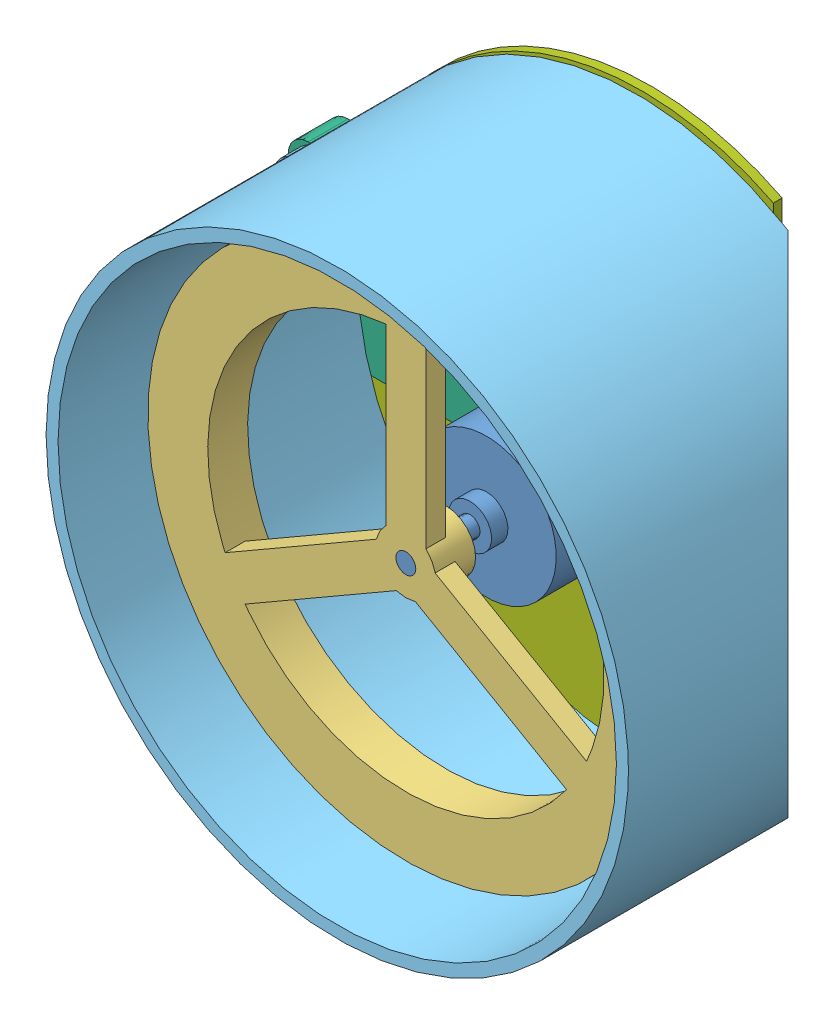
SolidWorks assembly Axis, configuration Default. Lengths in mm.
Overall size (176.68 176.68 95.5).
17 component instances, 7 part files, 42 mates.
Components (placement in the parent):
- Motor-1: Motor [Default] x (0.707107 0.707107 0) z (0.707107 -0.707107 0) size (35 53.5 35)
- Motor Plate-1: Motor Plate [Default] at (0 0 -26.65) x (0.707107 0.707107 0) z (-0.707107 0.707107 0) size (50 2.8 50)
- Reaction Wheel-1: Reaction Wheel [Default] at (0 0 26.75) x (0.5 -0.866025 0) z (-0.866025 -0.5 0) size (129.34 10 129.34)
- Screw-1: Screw [M3x5.5 Flat] at (8.4853 8.4853 -23.3783) x (0.707107 0.707107 0) z (-0.707107 0.707107 0) size (5 7.2 5)
- Screw-2: Screw [M3x5.5 Flat] at (6.5407 -6.5407 -23.3783) x (0.707107 0.707107 0) z (-0.707107 0.707107 0) size (5 7.2 5)
- Screw-3: Screw [M3x5.5 Flat] at (-6.5407 6.5407 -23.3783) x (0.707107 0.707107 0) z (-0.707107 0.707107 0) size (5 7.2 5)
- Screw-4: Screw [M3x5.5 Flat] at (-8.4853 -8.4853 -23.3783) x (0.707107 0.707107 0) z (-0.707107 0.707107 0) size (5 7.2 5)
- Screw-5: Screw [M3x25 Flat] at (-14.92 14.92 -38.525) x (0.999986 0.005309 0) z (0.005309 -0.999986 0) size (6 25 6)
- Screw-6: Screw [M3x25 Flat] at (-14.92 -14.92 -38.525) x (0.707107 0.707107 0) z (0.707107 -0.707107 0) size (6 25 6)
- Screw-7: Screw [M3x25 Flat] at (14.92 -14.92 -38.525) x (0.707107 0.707107 0) z (0.707107 -0.707107 0) size (6 25 6)
- Screw-8: Screw [M3x25 Flat] at (14.92 14.92 -38.525) x (0.707107 0.707107 0) z (0.707107 -0.707107 0) size (6 25 6)
- Shield-1: Shield [Default] at (0 0 6.45) size (159 146 75)
- Screw-9: Screw [M3x25 Flat] at (-79.5 14.92 -39.875) x (0.707107 0.707107 0) z (0.707107 -0.707107 0) size (6 25 6)
- Screw-10: Screw [M3x25 Flat] at (-79.5 -14.92 -39.875) x (0.707107 0.707107 0) z (0.707107 -0.707107 0) size (6 25 6)
- Shock Plate-1: Shock Plate [Default] at (-32.29 0 -36.05) x (-1 0 0) z (0 1 0) size (110 10 42.84)
- Rear Shield-1: Rear Shield [Wire Holes] at (0.0004 0 -33.5) x (1 0 0) z (0 -1 0) size (105.21 2.2 71.58)
- Rear Shield-2: Rear Shield [Default] at (0.0004 0 -33.5) x (1 0 0) z (0 1 0) size (105.21 2.2 71.58)
Mates (geometry in assembly coordinates):
- Coincident2: coincident aligned: plane of Motor-1 through (0 0 0) normal (0 0 1)
- Concentric1: concentric anti-aligned: cylinder of Motor-1 through (0 0 -45.7891) axis (0 0 -1) radius 2.5; cylinder of Motor Plate-1 through (0 0 -28.05) axis (0 0 1) radius 5.75
- Coincident4: coincident anti-aligned: plane of Motor-1 through (1.7678 1.7678 -25.25) normal (0 0 -1); plane of Motor Plate-1 through (14.92 -14.92 -25.25) normal (0 0 1)
- Concentric2: concentric anti-aligned: cylinder of Motor-1 through (8.4853 8.4853 -20.25) axis (0 0 -1) radius 1.5; cylinder of Motor Plate-1 through (8.4853 8.4853 -28.05) axis (0 0 1) radius 1.5
- Concentric3: concentric anti-aligned: cylinder of Motor-1 through (6.5407 -6.5407 -20.25) axis (0 0 -1) radius 1.5; cylinder of Motor Plate-1 through (6.5407 -6.5407 -28.05) axis (0 0 1) radius 1.5
- Concentric4: concentric aligned: cylinder of Motor Plate-1 through (8.4853 8.4853 -28.05) axis (0 0 1) radius 1.5; cylinder of Screw-1 through (8.4853 8.4853 -17.6716) axis (0 0 1) radius 1.35
- Coincident6: coincident aligned: cone of Motor Plate-1 through (8.4853 8.4853 -26.35) axis (0 0 1); cone of Screw-1 through (8.4853 8.4853 -26.1283) axis (0 0 1)
- Concentric9: concentric aligned: cylinder of Motor Plate-1 through (6.5407 -6.5407 -28.05) axis (0 0 1) radius 1.5; cylinder of Screw-2 through (6.5407 -6.5407 -17.6716) axis (0 0 1) radius 1.35
- Coincident7: coincident aligned: cone of Motor Plate-1 through (6.5407 -6.5407 -26.35) axis (0 0 1); cone of Screw-2 through (6.5407 -6.5407 -26.1283) axis (0 0 1)
- Concentric10: concentric aligned: cylinder of Motor Plate-1 through (-6.5407 6.5407 -28.05) axis (0 0 1) radius 1.5; cylinder of Screw-3 through (-6.5407 6.5407 -17.6716) axis (0 0 1) radius 1.35
- Coincident8: coincident aligned: cone of Motor Plate-1 through (-6.5407 6.5407 -26.35) axis (0 0 1); cone of Screw-3 through (-6.5407 6.5407 -26.1283) axis (0 0 1)
- Concentric11: concentric aligned: cylinder of Motor Plate-1 through (-8.4853 -8.4853 -28.05) axis (0 0 1) radius 1.5; cylinder of Screw-4 through (-8.4853 -8.4853 -17.6716) axis (0 0 1) radius 1.35
- Coincident9: coincident aligned: cone of Motor Plate-1 through (-8.4853 -8.4853 -26.35) axis (0 0 1); cone of Screw-4 through (-8.4853 -8.4853 -26.1283) axis (0 0 1)
- Concentric12: concentric anti-aligned: cylinder of Motor-1 through (0 0 -45.7891) axis (0 0 -1) radius 2.5; cylinder of Reaction Wheel-1 through (0 0 16.75) axis (0 0 1) radius 2.5
- Coincident10: coincident aligned: plane of Motor-1 through (0 0 26.75) normal (0 0 1); plane of Reaction Wheel-1 through (0 0 26.75) normal (0 0 1)
- Parallel1: parallel aligned: plane of Reaction Wheel-1 through (5 5.5902 21.75) normal (1 0 0)
- Concentric13: concentric anti-aligned: cylinder of Motor Plate-1 through (14.92 14.92 -28.05) axis (0 0 1) radius 1.5; cylinder of Screw-8 through (14.92 14.92 -44.2316) axis (0 0 -1) radius 1.35
- Coincident12: coincident aligned: cone of Motor Plate-1 through (14.92 14.92 -25.25) axis (0 0 -1); cone of Screw-8 through (14.92 14.92 -26.85) axis (0 0 -1)
- Concentric14: concentric anti-aligned: cylinder of Motor Plate-1 through (-14.92 14.92 -28.05) axis (0 0 1) radius 1.5; cylinder of Screw-5 through (-14.92 14.92 -44.2316) axis (0 0 -1) radius 1.35
- Coincident13: coincident aligned: cone of Motor Plate-1 through (-14.92 14.92 -25.25) axis (0 0 -1); cone of Screw-5 through (-14.92 14.92 -26.85) axis (0 0 -1)
- Concentric15: concentric anti-aligned: cylinder of Motor Plate-1 through (14.92 -14.92 -28.05) axis (0 0 1) radius 1.5; cylinder of Screw-7 through (14.92 -14.92 -44.2316) axis (0 0 -1) radius 1.35
- Coincident14: coincident aligned: cone of Motor Plate-1 through (14.92 -14.92 -25.25) axis (0 0 -1); cone of Screw-7 through (14.92 -14.92 -26.85) axis (0 0 -1)
- Concentric16: concentric anti-aligned: cylinder of Motor Plate-1 through (-14.92 -14.92 -28.05) axis (0 0 1) radius 1.5; cylinder of Screw-6 through (-14.92 -14.92 -44.2316) axis (0 0 -1) radius 1.35
- Coincident15: coincident aligned: cone of Motor Plate-1 through (-14.92 -14.92 -25.25) axis (0 0 -1); cone of Screw-6 through (-14.92 -14.92 -26.85) axis (0 0 -1)
- Concentric18: concentric anti-aligned: cylinder of Reaction Wheel-1 through (0 0 16.75) axis (0 0 1) radius 64.67; cylinder of Shield-1 through (0 0 43.95) axis (0 0 -1) radius 70
- Concentric19: concentric aligned: cylinder of Screw-5 through (-14.92 14.92 -44.2316) axis (0 0 -1) radius 1.35; cylinder of Shield-1 through (-14.92 14.92 -28.05) axis (0 0 -1) radius 1.5
- Coincident16: coincident anti-aligned: plane of Motor Plate-1 through (14.92 -14.92 -28.05) normal (0 0 -1); plane of Shield-1 through (73.002 27.92 -28.05) normal (0 0 1)
- Coincident18: coincident aligned: plane of Shield-1 through (0 0 6.45) normal (0 1 0)
- Coincident20: coincident aligned: plane of Shield-1 through (0 0 6.45) normal (1 0 0)
- Concentric20: concentric aligned: cylinder of Shield-1 through (-79.5 14.92 -26.05) axis (0 0 -1) radius 1.5; cylinder of Screw-9 through (-79.5 14.92 -45.5816) axis (0 0 -1) radius 1.35
- Concentric21: concentric aligned: cylinder of Shield-1 through (-79.5 -14.92 -26.05) axis (0 0 -1) radius 1.5; cylinder of Screw-10 through (-79.5 -14.92 -45.5816) axis (0 0 -1) radius 1.35
- Coincident21: coincident aligned: cone of Shield-1 through (-79.5 14.92 -26.05) axis (0 0 -1); cone of Screw-9 through (-79.5 14.92 -28.2) axis (0 0 -1)
- Coincident22: coincident aligned: cone of Shield-1 through (-79.5 -14.92 -26.05) axis (0 0 -1); cone of Screw-10 through (-79.5 -14.92 -28.2) axis (0 0 -1)
- Coincident23: coincident anti-aligned: plane of Shield-1 through (0 0 -31.05) normal (0 0 -1); plane of Shock Plate-1 through (17.71 16.42 -31.05) normal (0 0 1)
- Concentric22: concentric aligned: cylinder of Screw-7 through (14.92 -14.92 -44.2316) axis (0 0 -1) radius 1.35; cylinder of Shock Plate-1 through (14.92 -14.92 -31.05) axis (0 0 -1) radius 1.75
- Concentric23: concentric aligned: cylinder of Screw-5 through (-14.92 14.92 -44.2316) axis (0 0 -1) radius 1.35; cylinder of Shock Plate-1 through (-14.92 14.92 -31.05) axis (0 0 -1) radius 1.75
- Width1: width anti-aligned: plane of Rear Shield-1 through (0.0004 0 -32.4) normal (0 0 1); plane of Shock Plate-1 through (0.0004 0 -34.6) normal (0 0 -1); plane of Rear Shield-1 through (-22.21 -21.42 -32.55) normal (0 0 -1); plane of Shock Plate-1 through (-22.21 -21.42 -34.45) normal (0 0 1)
- Coincident24: coincident anti-aligned: plane of Shock Plate-1 through (-22.21 -21.42 -32.55) normal (-1 0 0); plane of Rear Shield-1 through (-22.21 1.42 -32.4) normal (1 0 0)
- Coincident25: coincident anti-aligned: plane of Shock Plate-1 through (17.71 21.42 -31.05) normal (0 1 0); plane of Rear Shield-1 through (33 21.42 -32.4) normal (0 -1 0)
- Coincident26: coincident aligned: plane of Rear Shield-1 through (0.0004 0 -34.6) normal (0 0 -1); plane of Rear Shield-2 through (0.0004 0 -34.6) normal (0 0 -1)
- Coincident27: coincident anti-aligned: plane of Shock Plate-1 through (17.71 -21.42 -31.05) normal (0 -1 0); plane of Rear Shield-2 through (33 -21.42 -34.6) normal (0 1 0)
- Coincident28: coincident aligned: plane of Rear Shield-1 through (33 65.1155 -32.4) normal (1 0 0); plane of Rear Shield-2 through (33 -65.1155 -34.6) normal (1 0 0)
